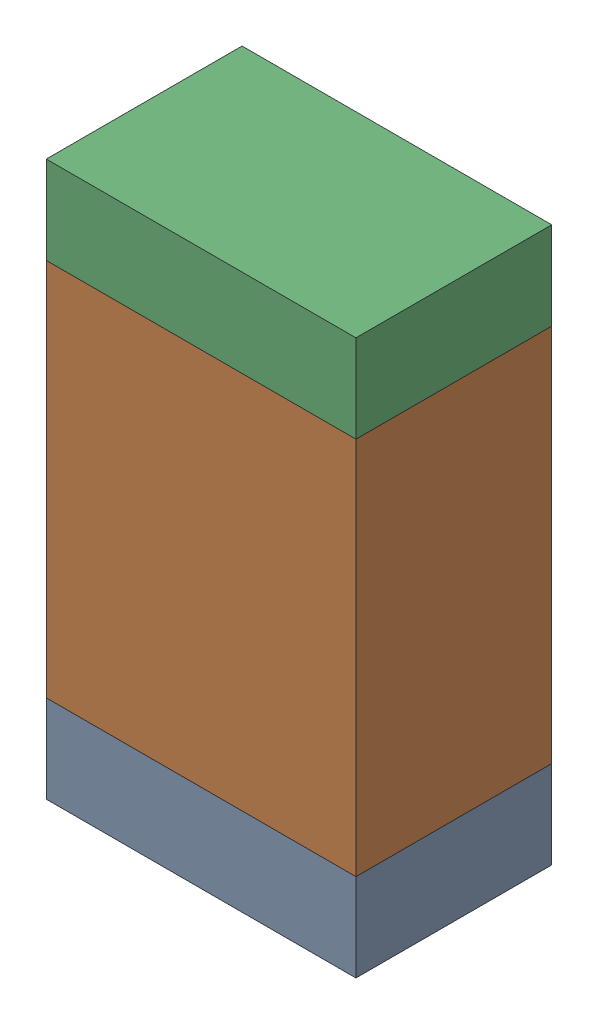
SolidWorks assembly R1-2, configuration Default. Lengths in mm.
Overall size (0.95 1.7 0.6).
6 component instances, 2 part files, 0 mates.
Components (placement in the parent):
- 959206216-2-1: 959206216-2 [Default] at (142.6211 77.6287 0) size (0.95 0.27 0.6)
  - Extruded-62-1: Extruded-62 [Default] at origin size (0.95 0.27 0.6)
- 959206352-2-1: 959206352-2 [Default] at (142.6211 78.3437 0) size (0.95 1.16 0.6)
  - Extruded-63-1: Extruded-63 [Default] at origin size (0.95 1.16 0.6)
- 959206216-2-2: 959206216-2 [Default] at (142.6211 79.0587 0) size (0.95 0.27 0.6)
  - Extruded-62-1: Extruded-62 [Default] at origin size (0.95 0.27 0.6)
